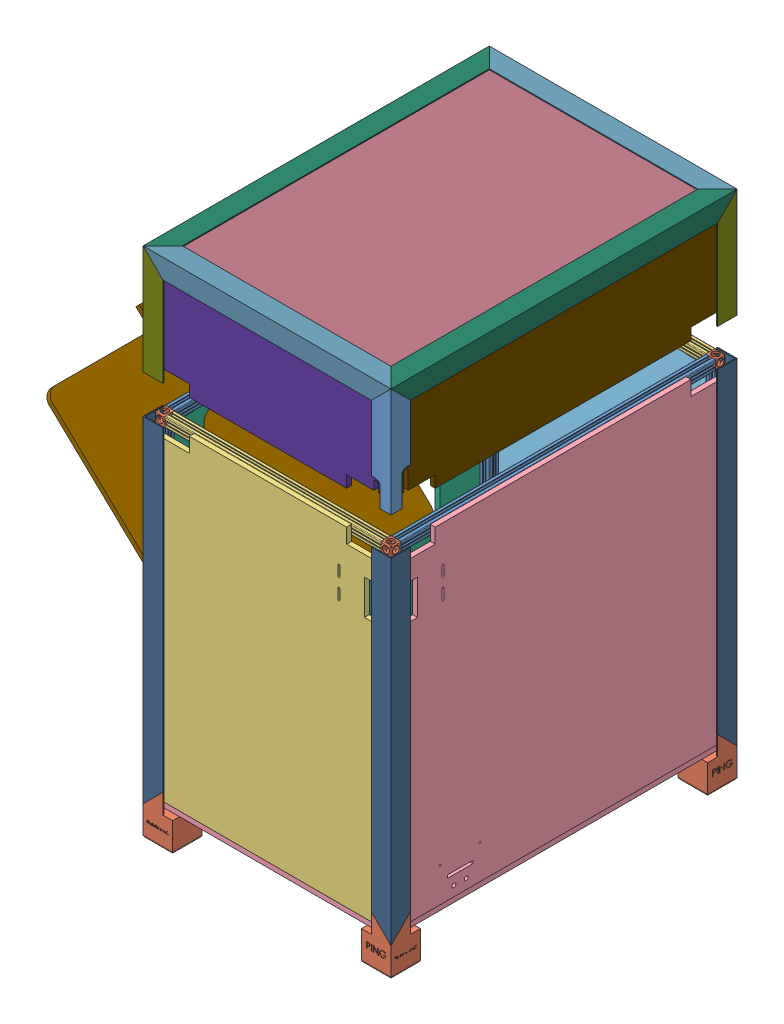
SolidWorks assembly carcasse, configuration Défaut. Lengths in mm.
Overall size (850.58 1042.31 704).
62 component instances, 25 part files, 71 mates.
Components (placement in the parent):
- cadre-1: cadre [Défaut] at (-215.194 -19.8636 -400) size (480 20 680)
  - prof_20x20x600mm-1: prof_20x20x600mm [End Finishing_Non-Machined End Finish Options_Type_Single_] at (-14.8937 4.0689 600) size (20 20 640)
  - Blocks-1: Blocks [Défaut] at (-4.8937 14.0689 1240) x (0 1 0) z (0 0 1) size (20 20 20)
  - prof_20x20x600mm-3: prof_20x20x600mm [End Finishing_Non-Machined End Finish Options_Type_Single_] at (445.1063 4.0689 600) size (20 20 640)
  - Blocks-3: Blocks [Défaut] at (-4.8937 -5.9311 580) x (0 0 -1) z (0 1 0) size (20 20 20)
  - Blocks-4: Blocks [Défaut] at (435.1063 14.0689 600) x (0 1 0) z (0 0 -1) size (20 20 20)
  - Blocks-5: Blocks [Défaut] at (435.1063 -5.9311 1260) x (0 0 1) z (0 1 0) size (20 20 20)
  - prof_20x20x400mm-1: prof_20x20x400mm [End Finishing_Non-Machined End Finish Options_Type_Single_] at (435.1063 4.0689 590) x (0 0 1) z (-1 0 0) size (20 20 440)
  - prof_20x20x400mm-2: prof_20x20x400mm [End Finishing_Non-Machined End Finish Options_Type_Single_] at (435.1063 4.0689 1250) x (0 0 1) z (-1 0 0) size (20 20 440)
- prof_20x20x600mm-1: prof_20x20x600mm [End Finishing_Non-Machined End Finish Options_Type_Single_] at (229.9123 -25.7947 190) x (1 0 0) z (0 -1 0) size (20 20 640)
- prof_20x20x600mm-2: prof_20x20x600mm [End Finishing_Non-Machined End Finish Options_Type_Single_] at (229.9123 -25.7947 850) x (1 0 0) z (0 -1 0) size (20 20 640)
- prof_20x20x600mm-3: prof_20x20x600mm [End Finishing_Non-Machined End Finish Options_Type_Single_] at (-230.0877 -25.7947 850) x (1 0 0) z (0 -1 0) size (20 20 640)
- prof_20x20x600mm-4: prof_20x20x600mm [End Finishing_Non-Machined End Finish Options_Type_Single_] at (-230.0877 -25.7947 190) x (1 0 0) z (0 -1 0) size (20 20 640)
- cadre-2: cadre [Défaut] at (215.0186 -671.7258 -400) x (-1 0 0) z (0 0 1) size (480 20 680)
  - prof_20x20x600mm-1: prof_20x20x600mm [End Finishing_Non-Machined End Finish Options_Type_Single_] at (-14.8937 4.0689 600) size (20 20 640)
  - Blocks-1: Blocks [Défaut] at (-4.8937 14.0689 1240) x (0 1 0) z (0 0 1) size (20 20 20)
  - prof_20x20x600mm-3: prof_20x20x600mm [End Finishing_Non-Machined End Finish Options_Type_Single_] at (445.1063 4.0689 600) size (20 20 640)
  - Blocks-3: Blocks [Défaut] at (-4.8937 -5.9311 580) x (0 0 -1) z (0 1 0) size (20 20 20)
  - Blocks-4: Blocks [Défaut] at (435.1063 14.0689 600) x (0 1 0) z (0 0 -1) size (20 20 20)
  - Blocks-5: Blocks [Défaut] at (435.1063 -5.9311 1260) x (0 0 1) z (0 1 0) size (20 20 20)
  - prof_20x20x400mm-1: prof_20x20x400mm [End Finishing_Non-Machined End Finish Options_Type_Single_] at (435.1063 4.0689 590) x (0 0 1) z (-1 0 0) size (20 20 440)
  - prof_20x20x400mm-2: prof_20x20x400mm [End Finishing_Non-Machined End Finish Options_Type_Single_] at (435.1063 4.0689 1250) x (0 0 1) z (-1 0 0) size (20 20 440)
- plaque_acrylique_680x670-2: plaque_acrylique_680x670 [Défaut] at (239.9123 -340.7947 520) x (0 0 -1) z (1 0 0) size (680 670 10)
- plaque_acrylique_380x670_G-1: plaque_acrylique_380x670_G [Défaut] at (49.9123 -350.7947 170) size (480 670 10)
- plaque_acrylique_680x670_porte-1: plaque_acrylique_680x670_porte [Défaut] at (-250.0877 -350.7947 520) x (0 0 -1) z (1 0 0) size (680 670 10)
- charniere-1: charniere [Défaut] at (-243.7309 -495.7947 776.2875) x (0 0 1) z (0 -1 0) size (40 29.08 53.23)
  - axe charnière-1: axe charnière [Défaut] at (-76.2875 9.8568 0) size (40 5 5)
  - batant charnière-1: batant charnière [Défaut] at (-76.2875 10.1991 -17.6196) size (40 7 33.5)
  - batant charnière-2: batant charnière [Défaut] at (-36.2875 -2.6626 12.4029) x (-1 0 0) z (0 0.723942 -0.689861) size (40 7 33.5)
- charniere-2: charniere [Défaut] at (-243.7309 -495.7947 376.2875) x (0 0 1) z (0 -1 0) size (40 29.08 53.23)
  - axe charnière-1: axe charnière [Défaut] at (-76.2875 9.8568 0) size (40 5 5)
  - batant charnière-1: batant charnière [Défaut] at (-76.2875 10.1991 -17.6196) size (40 7 33.5)
  - batant charnière-2: batant charnière [Défaut] at (-36.2875 -2.6626 12.4029) x (-1 0 0) z (0 0.723942 -0.689861) size (40 7 33.5)
- porte-1: porte [Défaut] at (-356.1448 -393.231 520) x (0 0 -1) z (0.689861 0.723942 0) size (480 480 10)
- eclisse_40x40x670_bisote_x1-1: eclisse_40x40x670_bisote_x1 [Défaut] at (-232.0877 -697.7947 188.1136) size (40 682 40)
- eclisse_40x40x670_bisote_x1-2: eclisse_40x40x670_bisote_x1 [Défaut] at (-231.9741 -697.7947 852) x (0 0 -1) z (1 0 0) size (40 682 40)
- eclisse_40x40x670_bisote_x1-3: eclisse_40x40x670_bisote_x1 [Défaut] at (231.9123 -695.7947 851.8864) x (-1 0 0) z (0 0 -1) size (40 682 40)
- eclisse_40x40x670_bisote_x1-4: eclisse_40x40x670_bisote_x1 [Défaut] at (231.7986 -695.7947 188) x (0 0 1) z (-1 0 0) size (40 682 40)
- couvercle-1: couvercle [Défaut] at (237.4119 176.2396 865) size (504 222 704)
  - plaque_acrylique_680x210-2: plaque_acrylique_680x210 [Défaut] at (-487.4996 -8.7215 -345) x (0 0 -1) z (1 0 0) size (680 210 10)
  - plaque_acrylique_380x210-2: plaque_acrylique_380x210 [Défaut] at (-187.4996 -8.7215 -695) size (480 210 10)
  - plaque_acrylique_380x680-1: plaque_acrylique_380x680 [Défaut] at (-187.4996 96.2785 -345) x (1 0 0) z (0 1 0) size (480 680 10)
  - eclisse_40x40x404_bisote_x2-1: eclisse_40x40x404_bisote_x2 [Défaut] at (14.5004 88.1649 -677) x (0 0 1) z (0 -1 0) size (40 504 40)
  - eclisse_40x40x704_bisote_x2-1: eclisse_40x40x704_bisote_x2 [Défaut] at (-5.6132 88.2785 -697) x (0 -1 0) z (-1 0 0) size (40 704 40)
  - eclisse_40x40x404_bisote_x2-2: eclisse_40x40x404_bisote_x2 [Défaut] at (-489.4996 88.1649 -13) x (0 0 -1) z (0 -1 0) size (40 504 40)
  - eclisse_40x40x704_bisote_x2-2: eclisse_40x40x704_bisote_x2 [Défaut] at (-469.4996 88.1649 -697) x (1 0 0) z (0 -1 0) size (40 704 40)
  - eclisse_40x40x222_bisote_x1-1: eclisse_40x40x222_bisote_x1 [Défaut] at (-469.386 108.2785 -677) x (0 0 1) z (1 0 0) size (40 222 40)
  - eclisse_40x40x222_bisote_x1-2: eclisse_40x40x222_bisote_x1 [Défaut] at (-5.4996 108.2785 -676.8864) x (-1 0 0) z (0 0 1) size (40 222 40)
  - eclisse_40x40x222_bisote_x1-4: eclisse_40x40x222_bisote_x1 [Défaut] at (-469.4996 108.2785 -13.1136) x (1 0 0) z (0 0 -1) size (40 222 40)
  - plaque_acrylique_380x210_Moteur-1: plaque_acrylique_380x210_Moteur [Défaut] at (-187.4996 -8.7215 -5) size (480 210 10)
  - plaque_acrylique_680x210_moteur-1: plaque_acrylique_680x210_moteur [Défaut] at (2.5004 -8.7215 -345) x (0 0 -1) z (1 0 0) size (680 210 10)
  - eclisse_40x40x222_bisote_x1_Moteur-1: eclisse_40x40x222_bisote_x1_Moteur [Défaut] at (-5.6132 108.2785 -13) x (0 0 -1) z (-1 0 0) size (40 222 40)
- Pied-1: Pied [Défaut] at (191.9123 -695.7947 228) x (-1 0 0) z (0 -1 0) size (60 60 100)
- Pied-2: Pied [Défaut] at (191.9123 -695.7947 812) x (0 0 -1) z (0 -1 0) size (60 60 100)
- Pied-3: Pied [Défaut] at (-192.0877 -697.7947 812) x (1 0 0) z (0 -1 0) size (60 60 100)
- Pied-4: Pied [Défaut] at (-192.0877 -695.7947 228) x (0 0 1) z (0 -1 0) size (60 60 100)
- eclisse_bas_40x40x704-2: eclisse_bas_40x40x704 [Défaut] at (-232.0877 -677.681 832) x (1 0 0) z (0 1 0) size (40 624 40) (hidden)
- eclisse_bas_40x40x404-1: eclisse_bas_40x40x404 [Défaut] at (-222.0877 -677.681 196) x (0 0 1) z (0 1 0) size (40 424 40) (hidden)
- eclisse_bas_40x40x404-2: eclisse_bas_40x40x404 [Défaut] at (211.9123 -677.681 852) x (0 0 -1) z (0 1 0) size (40 424 40) (hidden)
- eclisse_bas_support_Z_40x40x704-1: eclisse_bas_support_Z_40x40x704 [Défaut] at (231.7986 -677.7947 832) x (0 1 0) z (-1 0 0) size (40 624 40) (hidden)
- plaque_acrylique_380x670_D-2: plaque_acrylique_380x670_D [Défaut] at (-50.0877 -340.7947 870) x (-1 0 0) z (0 0 -1) size (480 670 10)
- plaque_acrylique_bas_380x680-1: plaque_acrylique_bas_380x680 [Défaut] at (49.9123 -695.7947 520) x (1 0 0) z (0 1 0) size (480 680 10)
Mates (geometry in assembly coordinates):
- Coïncidente50: coincident anti-aligned: plane of plaque_acrylique_680x670_porte-1 through (-250.0877 -350.7947 520) normal (-1 0 0); plane of charniere-1/batant charnière-1 through (-250.0877 -535.7947 740) normal (1 0 0)
- Coïncidente51: coincident anti-aligned: plane of plaque_acrylique_680x670_porte-1 through (-250.0877 -350.7947 520) normal (-1 0 0); plane of charniere-2/batant charnière-1 through (-250.0877 -535.7947 340) normal (1 0 0)
- Distance4: distance = 20 mm anti-aligned: plane of charniere-2/batant charnière-1 through (-253.5877 -495.7947 300) normal (0 0 -1); plane of plaque_acrylique_680x670_porte-1 through (-250.0877 -75.7947 280) normal (0 0 1)
- Coïncidente54: coincident aligned: line of plaque_acrylique_680x670_porte-1 through (-250.0877 -495.7947 740) axis (0 0 -1); line of charniere-2/batant charnière-1 through (-250.0877 -495.7947 340) axis (0 0 -1)
- Distance5: distance = 20 mm anti-aligned: plane of plaque_acrylique_680x670_porte-1 through (-250.0877 -75.7947 760) normal (0 0 -1); plane of charniere-1/batant charnière-1 through (-253.5877 -495.7947 740) normal (0 0 1)
- Coïncidente57: coincident aligned: line of plaque_acrylique_680x670_porte-1 through (-250.0877 -495.7947 740) axis (0 0 -1); line of charniere-1/batant charnière-1 through (-250.0877 -495.7947 740) axis (0 0 -1)
- Coïncidente62: coincident anti-aligned: plane of charniere-1/batant charnière-2 through (-280.1309 -465.6664 700) normal (0.689861 0.723942 0); plane of porte-1 through (-576.947 -182.8234 550) normal (-0.689861 -0.723942 0)
- Coïncidente63: coincident anti-aligned: line of charniere-1/batant charnière-2 through (-251.1732 -493.2609 720) axis (0 0 1); line of porte-1 through (-251.1732 -493.2609 740) axis (0 0 -1)
- Coïncidente64: coincident anti-aligned: plane of plaque_acrylique_680x670_porte-1 through (-250.0877 -75.7947 760) normal (0 0 -1); plane of porte-1 through (-548.3301 -196.2798 760) normal (0 0 1)
- Coïncidente66: coincident anti-aligned: plane of plaque_acrylique_680x670_porte-1 through (-250.0877 -350.7947 520) normal (-1 0 0); plane of eclisse_40x40x670_bisote_x1-1 through (-250.0877 -15.7947 170) normal (1 0 0)
- Coïncidente67: coincident aligned: plane of plaque_acrylique_680x670_porte-1 through (-240.0877 -15.7947 860) normal (0 1 0); plane of eclisse_40x40x670_bisote_x1-1 through (-232.0877 -15.7947 188.1136) normal (0 1 0)
- Coïncidente68: coincident anti-aligned: plane of plaque_acrylique_680x670-2 through (249.9123 -340.7947 520) normal (1 0 0); plane of eclisse_40x40x670_bisote_x1-4 through (249.9123 -13.7947 170) normal (-1 0 0)
- Coïncidente72: coincident anti-aligned: plane of plaque_acrylique_680x670_porte-1 through (-250.0877 -350.7947 520) normal (-1 0 0); plane of eclisse_40x40x670_bisote_x1-2 through (-250.0877 -15.7947 870) normal (1 0 0)
- Coïncidente74: coincident anti-aligned: plane of plaque_acrylique_680x670-2 through (249.9123 -340.7947 520) normal (1 0 0); plane of eclisse_40x40x670_bisote_x1-3 through (249.9123 -13.7947 870) normal (-1 0 0)
- Coïncidente100: coincident: plane of plaque_acrylique_680x670_porte-1 through (-240.0877 -15.7947 860) normal (0 1 0); line of eclisse_40x40x670_bisote_x1-2 through (-250.0877 -15.7947 870) axis (0 0 -1)
- Coïncidente126: coincident anti-aligned: plane of eclisse_40x40x670_bisote_x1-3 through (251.9123 -695.7947 282) normal (-0.707107 -0.707107 0); plane of Pied-2 through (211.9123 -655.7947 870) normal (0.707107 0.707107 0)
- Coïncidente130: coincident anti-aligned: plane of eclisse_40x40x670_bisote_x1-2 through (337.9123 -697.7947 872) normal (0 -0.707107 -0.707107); plane of Pied-3 through (-250.0877 -657.7947 832) normal (0 0.707107 0.707107)
- Coïncidente132: coincident anti-aligned: plane of plaque_acrylique_680x670_porte-1 through (-250.0877 -350.7947 520) normal (-1 0 0); plane of eclisse_bas_40x40x704-2 through (-250.0877 -695.7947 208) normal (1 0 0)
- Coïncidente134: coincident anti-aligned: line of eclisse_40x40x670_bisote_x1-2 through (-252.0877 -15.7947 832) axis (0 -1 0); line of eclisse_bas_40x40x704-2 through (-252.0877 -697.7947 832) axis (0 1 0)
- Coïncidente140: coincident anti-aligned: line of Pied-3 through (-212.0877 -657.7947 872) axis (0 -1 0); line of eclisse_bas_40x40x404-2 through (-212.0877 -697.7947 872) axis (0 1 0)
- Coïncidente142: coincident anti-aligned: plane of plaque_acrylique_680x670-2 through (249.9123 -340.7947 520) normal (1 0 0); plane of eclisse_bas_support_Z_40x40x704-1 through (249.9123 -695.7947 208) normal (-1 0 0)
- Coïncidente144: coincident anti-aligned: plane of Pied-2 through (249.9123 -655.7947 832) normal (0 0 -1); plane of eclisse_bas_support_Z_40x40x704-1 through (231.7986 -677.7947 832) normal (0 0 1)
- Coïncidente151: coincident anti-aligned: plane of Pied-3 through (-192.0877 -697.7947 812) normal (0 1 0); plane of eclisse_bas_40x40x404-2 through (-212.0877 -697.7947 872) normal (0 -1 0)
- Coïncidente156: coincident anti-aligned: plane of eclisse_bas_40x40x404-2 through (-212.0877 -695.7947 870) normal (0 0 -1); plane of plaque_acrylique_380x670_D-2 through (-50.0877 -340.7947 870) normal (0 0 1)
- Coïncidente157: coincident anti-aligned: plane of eclisse_40x40x670_bisote_x1-2 through (-250.0877 -15.7947 870) normal (0 0 -1); plane of plaque_acrylique_380x670_D-2 through (-50.0877 -340.7947 870) normal (0 0 1)
- Coïncidente158: coincident anti-aligned: plane of eclisse_40x40x670_bisote_x1-3 through (249.9123 -13.7947 870) normal (0 0 -1); plane of plaque_acrylique_380x670_D-2 through (-50.0877 -340.7947 870) normal (0 0 1)
- Coïncidente163: coincident anti-aligned: plane of cadre-1/Blocks-1 through (-240.0877 -25.7947 860) normal (0 -1 0); plane of prof_20x20x600mm-3 through (-238.5877 -25.7947 858.5) normal (0 1 0)
- Coïncidente164: coincident aligned: plane of cadre-1/Blocks-1 through (-240.0877 -25.7947 860) normal (-1 0 0); plane of prof_20x20x600mm-3 through (-240.0877 -665.7947 853.75) normal (-1 0 0)
- Coïncidente165: coincident aligned: plane of cadre-1/Blocks-1 through (-220.0877 -5.7947 860) normal (0 0 1); plane of prof_20x20x600mm-3 through (-233.8377 -665.7947 860) normal (0 0 1)
- Coïncidente166: coincident anti-aligned: plane of prof_20x20x600mm-3 through (-238.5877 -665.7947 858.5) normal (0 -1 0); plane of cadre-2/Blocks-5 through (-220.0877 -665.7947 860) normal (0 1 0)
- Coïncidente167: coincident aligned: plane of prof_20x20x600mm-3 through (-233.8377 -665.7947 860) normal (0 0 1); plane of cadre-2/Blocks-5 through (-240.0877 -685.7947 860) normal (0 0 1)
- Coïncidente168: coincident aligned: plane of prof_20x20x600mm-3 through (-240.0877 -665.7947 853.75) normal (-1 0 0); plane of cadre-2/Blocks-5 through (-240.0877 -685.7947 840) normal (-1 0 0)
- Coïncidente169: coincident anti-aligned: plane of prof_20x20x600mm-2 through (221.4123 -665.7947 858.5) normal (0 -1 0); plane of cadre-2/Blocks-1 through (239.9123 -665.7947 860) normal (0 1 0)
- Coïncidente170: coincident aligned: plane of prof_20x20x600mm-2 through (226.1623 -665.7947 860) normal (0 0 1); plane of cadre-2/Blocks-1 through (219.9123 -685.7947 860) normal (0 0 1)
- Coïncidente171: coincident aligned: plane of prof_20x20x600mm-2 through (239.9123 -665.7947 853.75) normal (1 0 0); plane of cadre-2/Blocks-1 through (239.9123 -665.7947 860) normal (1 0 0)
- Coïncidente172: coincident anti-aligned: plane of prof_20x20x600mm-1 through (221.4123 -665.7947 198.5) normal (0 -1 0); plane of cadre-2/Blocks-3 through (219.9123 -665.7947 180) normal (0 1 0)
- Coïncidente173: coincident aligned: plane of prof_20x20x600mm-1 through (239.9123 -665.7947 193.75) normal (1 0 0); plane of cadre-2/Blocks-3 through (239.9123 -685.7947 200) normal (1 0 0)
- Coïncidente174: coincident aligned: plane of prof_20x20x600mm-1 through (233.6623 -665.7947 180) normal (0 0 -1); plane of cadre-2/Blocks-3 through (239.9123 -685.7947 180) normal (0 0 -1)
- Coïncidente175: coincident aligned: plane of cadre-1/Blocks-3 through (-240.0877 -5.7947 200) normal (-1 0 0); plane of prof_20x20x600mm-4 through (-240.0877 -665.7947 186.25) normal (-1 0 0)
- Coïncidente176: coincident aligned: plane of cadre-1/Blocks-3 through (-240.0877 -5.7947 180) normal (0 0 -1); plane of prof_20x20x600mm-4 through (-233.8377 -665.7947 180) normal (0 0 -1)
- Coïncidente177: coincident anti-aligned: plane of cadre-1/Blocks-3 through (-220.0877 -25.7947 180) normal (0 -1 0); plane of prof_20x20x600mm-4 through (-238.5877 -25.7947 198.5) normal (0 1 0)
- Coïncidente182: coincident aligned: plane of cadre-1/prof_20x20x400mm-2 through (-220.0877 -5.7947 853.75) normal (0 1 0); plane of plaque_acrylique_380x670_D-2 through (239.9123 -5.7947 860) normal (0 1 0)
- Coïncidente183: coincident aligned: plane of prof_20x20x600mm-2 through (239.9123 -665.7947 853.75) normal (1 0 0); plane of plaque_acrylique_380x670_D-2 through (239.9123 -5.7947 860) normal (1 0 0)
- Coïncidente184: coincident aligned: plane of cadre-1/prof_20x20x600mm-3 through (233.6623 -5.7947 840) normal (0 1 0); plane of plaque_acrylique_680x670-2 through (249.9123 -5.7947 860) normal (0 1 0)
- Coïncidente185: coincident anti-aligned: plane of cadre-1/prof_20x20x600mm-3 through (239.9123 -12.0447 840) normal (1 0 0); plane of plaque_acrylique_680x670-2 through (239.9123 -340.7947 520) normal (-1 0 0)
- Coïncidente186: coincident aligned: plane of cadre-1/prof_20x20x400mm-2 through (-220.0877 -12.0447 860) normal (0 0 1); plane of plaque_acrylique_680x670-2 through (249.9123 -5.7947 860) normal (0 0 1)
- Coïncidente187: coincident aligned: plane of cadre-1/prof_20x20x400mm-1 through (-220.0877 -19.5447 180) normal (0 0 -1); plane of plaque_acrylique_680x670_porte-1 through (-240.0877 -15.7947 180) normal (0 0 -1)
- Coïncidente191: coincident anti-aligned: plane of cadre-2/prof_20x20x400mm-1 through (219.9123 -685.7947 193.75) normal (0 -1 0); plane of plaque_acrylique_bas_380x680-1 through (49.9123 -685.7947 520) normal (0 1 0)
- Coïncidente192: coincident aligned: plane of cadre-2/prof_20x20x400mm-2 through (219.9123 -679.5447 860) normal (0 0 1); plane of plaque_acrylique_bas_380x680-1 through (-240.0877 -685.7947 860) normal (0 0 1)
- Coïncidente193: coincident aligned: plane of cadre-2/prof_20x20x600mm-1 through (239.9123 -679.5447 840) normal (1 0 0); plane of plaque_acrylique_bas_380x680-1 through (239.9123 -685.7947 180) normal (1 0 0)
- Coïncidente195: coincident anti-aligned: plane of Pied-2 through (191.9123 -695.7947 812) normal (0 1 0); plane of plaque_acrylique_bas_380x680-1 through (49.9123 -695.7947 520) normal (0 -1 0)
- Coaxiale1: concentric anti-aligned: cylinder of Pied-1 through (219.9123 -675.7947 200) axis (0 -1 0) radius 12; cylinder of plaque_acrylique_bas_380x680-1 through (219.9123 -695.7947 200) axis (0 1 0) radius 12.5
- Coïncidente198: coincident anti-aligned: plane of Pied-1 through (191.9123 -695.7947 228) normal (0 1 0); plane of plaque_acrylique_bas_380x680-1 through (49.9123 -695.7947 520) normal (0 -1 0)
- Coïncidente199: coincident anti-aligned: line of eclisse_40x40x670_bisote_x1-4 through (251.9123 -695.7947 168) axis (0 0.707107 0.707107); line of Pied-1 through (251.9123 -655.7947 208) axis (0 -0.707107 -0.707107)
- Coaxiale2: concentric anti-aligned: cylinder of Pied-2 through (219.9123 -675.7947 840) axis (0 -1 0) radius 12; cylinder of plaque_acrylique_bas_380x680-1 through (219.9123 -695.7947 840) axis (0 1 0) radius 12.5
- Coïncidente200: coincident anti-aligned: plane of Pied-2 through (191.9123 -695.7947 812) normal (0 1 0); plane of plaque_acrylique_bas_380x680-1 through (49.9123 -695.7947 520) normal (0 -1 0)
- Coïncidente201: coincident anti-aligned: plane of plaque_acrylique_680x670-2 through (249.9123 -340.7947 520) normal (1 0 0); plane of Pied-2 through (249.9123 -655.7947 870) normal (-1 0 0)
- Coïncidente202: coincident anti-aligned: line of eclisse_40x40x670_bisote_x1-3 through (251.9123 -695.7947 872) axis (-0.707107 0.707107 0); line of Pied-2 through (211.9123 -655.7947 872) axis (0.707107 -0.707107 0)
- Coïncidente203: coincident aligned: plane of cadre-2/prof_20x20x600mm-3 through (-233.8377 -685.7947 840) normal (0 -1 0); plane of plaque_acrylique_680x670_porte-1 through (-240.0877 -685.7947 860) normal (0 -1 0)
- Coaxiale3: concentric anti-aligned: cylinder of Pied-3 through (-220.0877 -677.7947 840) axis (0 -1 0) radius 12; cylinder of plaque_acrylique_bas_380x680-1 through (-220.0877 -695.7947 840) axis (0 1 0) radius 12.5
- Coïncidente204: coincident anti-aligned: plane of prof_20x20x600mm-1 through (233.6623 -665.7947 180) normal (0 0 -1); plane of plaque_acrylique_380x670_G-1 through (49.9123 -350.7947 180) normal (0 0 1)
- Coïncidente205: coincident aligned: plane of cadre-2/prof_20x20x400mm-1 through (219.9123 -685.7947 186.25) normal (0 -1 0); plane of plaque_acrylique_380x670_G-1 through (-240.0877 -685.7947 180) normal (0 -1 0)
- Coïncidente206: coincident aligned: plane of prof_20x20x600mm-1 through (239.9123 -665.7947 186.25) normal (1 0 0); plane of plaque_acrylique_380x670_G-1 through (239.9123 -15.7947 180) normal (1 0 0)
- Coïncidente207: coincident anti-aligned: plane of prof_20x20x600mm-4 through (-240.0877 -665.7947 186.25) normal (-1 0 0); plane of plaque_acrylique_680x670_porte-1 through (-240.0877 -350.7947 520) normal (1 0 0)
- Coïncidente208: coincident anti-aligned: plane of plaque_acrylique_380x670_G-1 through (49.9123 -350.7947 170) normal (0 0 -1); plane of eclisse_40x40x670_bisote_x1-1 through (-250.0877 -15.7947 170) normal (0 0 1)
- Coïncidente210: coincident anti-aligned: plane of plaque_acrylique_380x670_G-1 through (49.9123 -350.7947 170) normal (0 0 -1); plane of eclisse_40x40x670_bisote_x1-4 through (249.9123 -13.7947 170) normal (0 0 1)
- Coaxiale4: concentric anti-aligned: cylinder of Pied-4 through (-220.0877 -675.7947 200) axis (0 -1 0) radius 12; cylinder of plaque_acrylique_bas_380x680-1 through (-220.0877 -695.7947 200) axis (0 1 0) radius 12.5
- Coïncidente211: coincident anti-aligned: plane of Pied-4 through (-192.0877 -695.7947 228) normal (0 1 0); plane of plaque_acrylique_bas_380x680-1 through (49.9123 -695.7947 520) normal (0 -1 0)
- Parallèle4: parallel anti-aligned: line of eclisse_40x40x670_bisote_x1-1 through (-252.0877 -697.7947 168) axis (0.707107 0.707107 0); line of Pied-4 through (-212.0877 -655.7947 168) axis (-0.707107 -0.707107 0)
- Coïncidente215: coincident aligned: plane of plaque_acrylique_680x670_porte-1 through (-250.0877 -350.7947 520) normal (-1 0 0); plane of couvercle-1/plaque_acrylique_680x210-2 through (-250.0877 167.5181 520) normal (-1 0 0)
- Coïncidente216: coincident aligned: plane of couvercle-1/plaque_acrylique_380x210_Moteur-1 through (49.9123 167.5181 870) normal (0 0 1); plane of plaque_acrylique_380x670_D-2 through (-50.0877 -340.7947 870) normal (0 0 1)
